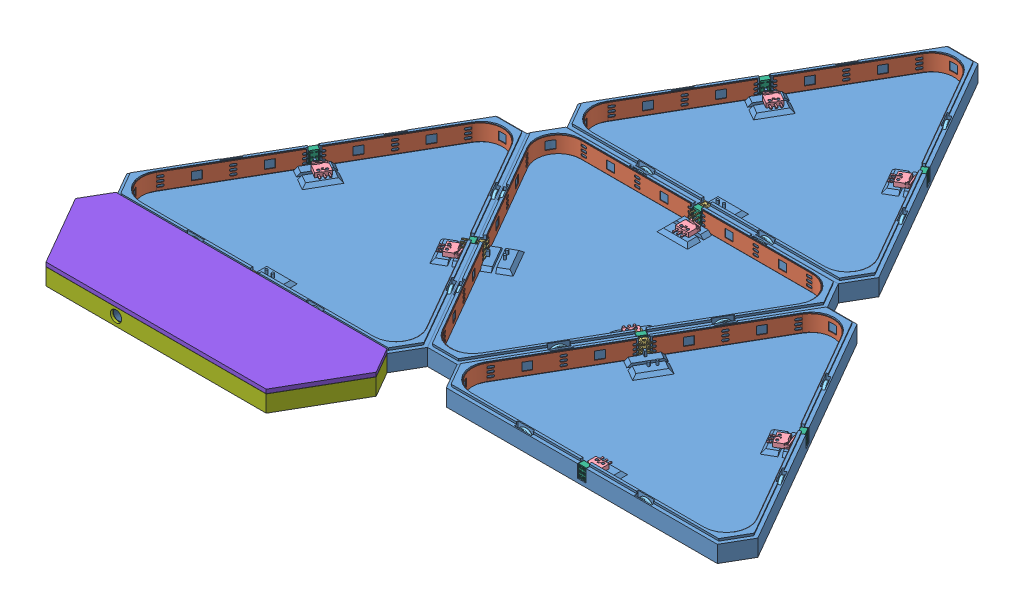
SolidWorks assembly smartleaf_triangle_multi, configuration Défaut. Lengths in mm.
Overall size (448.34 14.05 459.74).
75 component instances, 12 part files, 12 mates.
Components (placement in the parent):
- smartleaf_triangle-1: smartleaf_triangle [Défaut] at (-32.3609 -8.2691 146.7938) size (187.52 14.05 190.18)
  - smartleaf_triangle_bottom-1: smartleaf_triangle_bottom [Défaut] at origin size (187.52 12 162.4)
  - smartleaf_triangle_top-1: smartleaf_triangle_top [Défaut] at (0 13 0) x (1 0 0) z (0 0 -1) size (136.52 2.5 118.23) (hidden)
  - Strip_led_ws2812_30leds-m-1: Strip_led_ws2812_30leds-m [Défaut] at (-125.2022 6.5 104.9223) x (0.5 0 -0.866025) z (0.866025 0 0.5) size (82.78 10 80.82)
  - Strip_led_ws2812_30leds-m-2: Strip_led_ws2812_30leds-m [Défaut] at (153.4665 6.5 55.9671) x (-1 0 0) z (0 0 -1) size (82.78 10 80.82)
  - Strip_led_ws2812_30leds-m-3: Strip_led_ws2812_30leds-m [Défaut] at (-28.2643 6.5 -160.8894) x (0.5 0 0.866025) z (-0.866025 0 0.5) size (82.78 10 80.82)
  - TSM_103_02_T_DV-1: TSM_103_02_T_DV [Défaut] at (0 6.5 57.4721) x (0 -1 0) z (-1 0 0) size (7.62 11.94 7.44)
  - TS0101F020P-1: TS0101F020P [Défaut] at (42.2907 4.35 -22.6845) x (-0.5 0 -0.866025) z (0.866025 0 -0.5) size (8.31 2.7 12.18)
  - TS0101F020P-5: TS0101F020P [Défaut] at (-40.7907 4.35 -25.2826) x (-0.5 0 0.866025) z (-0.866025 0 -0.5) size (8.31 2.7 12.18)
  - Aimant_10x2mm-1: Aimant_10x2mm [Défaut] at (37.5 6 56.4671) x (0.78482 -0.619723 0) z (0 0 1) size (10 10 2)
  - Aimant_10x2mm-2: Aimant_10x2mm [Défaut] at (-37.5 6 56.6671) x (0.873152 -0.487449 0) z (0 0 1) size (10 10 2)
  - Aimant_10x2mm-4: Aimant_10x2mm [Défaut] at (-67.8251 6 4.1424) x (-0.272453 -0.838497 0.471903) z (-0.866025 0 -0.5) size (10 10 2)
  - Aimant_10x2mm-6: Aimant_10x2mm [Défaut] at (-30.3251 6 -60.8095) x (-0.128011 -0.966671 0.221722) z (-0.866025 0 -0.5) size (10 10 2)
  - Aimant_10x2mm-8: Aimant_10x2mm [Défaut] at (30.3251 6 -60.8095) x (-0.4998 -0.028255 -0.86568) z (0.866025 0 -0.5) size (10 10 2)
  - Aimant_10x2mm-10: Aimant_10x2mm [Défaut] at (67.8251 6 4.1424) x (-0.49797 -0.09001 -0.86251) z (0.866025 0 -0.5) size (10 10 2)
  - 610006243021-1: 610006243021 [Défaut] at (-49.638 6.5 -28.6585) x (0 1 0) z (-0.866025 0 -0.5) size (7.62 7.21 3.7)
  - 610006243021-2: 610006243021 [Défaut] at (49.638 6.5 -28.6585) x (0 1 0) z (0.866025 0 -0.5) size (7.62 7.21 3.7)
- smartleaf_triangle-2: smartleaf_triangle [Défaut] at (70.6391 -8.2691 87.3267) x (0.5 0 0.866025) z (-0.866025 0 0.5) size (187.52 14.05 190.18)
  - smartleaf_triangle_bottom-1: smartleaf_triangle_bottom [Défaut] at origin size (187.52 12 162.4)
  - smartleaf_triangle_top-1: smartleaf_triangle_top [Défaut] at (0 13 0) x (1 0 0) z (0 0 -1) size (136.52 2.5 118.23) (hidden)
  - Strip_led_ws2812_30leds-m-1: Strip_led_ws2812_30leds-m [Défaut] at (-125.2022 6.5 104.9223) x (0.5 0 -0.866025) z (0.866025 0 0.5) size (82.78 10 80.82)
  - Strip_led_ws2812_30leds-m-2: Strip_led_ws2812_30leds-m [Défaut] at (153.4665 6.5 55.9671) x (-1 0 0) z (0 0 -1) size (82.78 10 80.82)
  - Strip_led_ws2812_30leds-m-3: Strip_led_ws2812_30leds-m [Défaut] at (-28.2643 6.5 -160.8894) x (0.5 0 0.866025) z (-0.866025 0 0.5) size (82.78 10 80.82)
  - TSM_103_02_T_DV-1: TSM_103_02_T_DV [Défaut] at (0 6.5 57.4721) x (0 -1 0) z (-1 0 0) size (7.62 11.94 7.44)
  - TS0101F020P-1: TS0101F020P [Défaut] at (42.2907 4.35 -22.6845) x (-0.5 0 -0.866025) z (0.866025 0 -0.5) size (8.31 2.7 12.18)
  - TS0101F020P-5: TS0101F020P [Défaut] at (-40.7907 4.35 -25.2826) x (-0.5 0 0.866025) z (-0.866025 0 -0.5) size (8.31 2.7 12.18)
  - Aimant_10x2mm-1: Aimant_10x2mm [Défaut] at (37.5 6 56.4671) x (0.78482 -0.619723 0) z (0 0 1) size (10 10 2)
  - Aimant_10x2mm-2: Aimant_10x2mm [Défaut] at (-37.5 6 56.6671) x (0.873152 -0.487449 0) z (0 0 1) size (10 10 2)
  - Aimant_10x2mm-4: Aimant_10x2mm [Défaut] at (-67.8251 6 4.1424) x (-0.272453 -0.838497 0.471903) z (-0.866025 0 -0.5) size (10 10 2)
  - Aimant_10x2mm-6: Aimant_10x2mm [Défaut] at (-30.3251 6 -60.8095) x (-0.128011 -0.966671 0.221722) z (-0.866025 0 -0.5) size (10 10 2)
  - Aimant_10x2mm-8: Aimant_10x2mm [Défaut] at (30.3251 6 -60.8095) x (-0.4998 -0.028255 -0.86568) z (0.866025 0 -0.5) size (10 10 2)
  - Aimant_10x2mm-10: Aimant_10x2mm [Défaut] at (67.8251 6 4.1424) x (-0.49797 -0.09001 -0.86251) z (0.866025 0 -0.5) size (10 10 2)
  - 610006243021-1: 610006243021 [Défaut] at (-49.638 6.5 -28.6585) x (0 1 0) z (-0.866025 0 -0.5) size (7.62 7.21 3.7)
  - 610006243021-2: 610006243021 [Défaut] at (49.638 6.5 -28.6585) x (0 1 0) z (0.866025 0 -0.5) size (7.62 7.21 3.7)
- smartleaf_triangle-3: smartleaf_triangle [Défaut] at (173.6391 -8.2691 146.7938) x (-0.5 0 0.866025) z (-0.866025 0 -0.5) size (187.52 14.05 190.18)
  - smartleaf_triangle_bottom-1: smartleaf_triangle_bottom [Défaut] at origin size (187.52 12 162.4)
  - smartleaf_triangle_top-1: smartleaf_triangle_top [Défaut] at (0 13 0) x (1 0 0) z (0 0 -1) size (136.52 2.5 118.23) (hidden)
  - Strip_led_ws2812_30leds-m-1: Strip_led_ws2812_30leds-m [Défaut] at (-125.2022 6.5 104.9223) x (0.5 0 -0.866025) z (0.866025 0 0.5) size (82.78 10 80.82)
  - Strip_led_ws2812_30leds-m-2: Strip_led_ws2812_30leds-m [Défaut] at (153.4665 6.5 55.9671) x (-1 0 0) z (0 0 -1) size (82.78 10 80.82)
  - Strip_led_ws2812_30leds-m-3: Strip_led_ws2812_30leds-m [Défaut] at (-28.2643 6.5 -160.8894) x (0.5 0 0.866025) z (-0.866025 0 0.5) size (82.78 10 80.82)
  - TSM_103_02_T_DV-1: TSM_103_02_T_DV [Défaut] at (0 6.5 57.4721) x (0 -1 0) z (-1 0 0) size (7.62 11.94 7.44)
  - TS0101F020P-1: TS0101F020P [Défaut] at (42.2907 4.35 -22.6845) x (-0.5 0 -0.866025) z (0.866025 0 -0.5) size (8.31 2.7 12.18)
  - TS0101F020P-5: TS0101F020P [Défaut] at (-40.7907 4.35 -25.2826) x (-0.5 0 0.866025) z (-0.866025 0 -0.5) size (8.31 2.7 12.18)
  - Aimant_10x2mm-1: Aimant_10x2mm [Défaut] at (37.5 6 56.4671) x (0.78482 -0.619723 0) z (0 0 1) size (10 10 2)
  - Aimant_10x2mm-2: Aimant_10x2mm [Défaut] at (-37.5 6 56.6671) x (0.873152 -0.487449 0) z (0 0 1) size (10 10 2)
  - Aimant_10x2mm-4: Aimant_10x2mm [Défaut] at (-67.8251 6 4.1424) x (-0.272453 -0.838497 0.471903) z (-0.866025 0 -0.5) size (10 10 2)
  - Aimant_10x2mm-6: Aimant_10x2mm [Défaut] at (-30.3251 6 -60.8095) x (-0.128011 -0.966671 0.221722) z (-0.866025 0 -0.5) size (10 10 2)
  - Aimant_10x2mm-8: Aimant_10x2mm [Défaut] at (30.3251 6 -60.8095) x (-0.4998 -0.028255 -0.86568) z (0.866025 0 -0.5) size (10 10 2)
  - Aimant_10x2mm-10: Aimant_10x2mm [Défaut] at (67.8251 6 4.1424) x (-0.49797 -0.09001 -0.86251) z (0.866025 0 -0.5) size (10 10 2)
  - 610006243021-1: 610006243021 [Défaut] at (-49.638 6.5 -28.6585) x (0 1 0) z (-0.866025 0 -0.5) size (7.62 7.21 3.7)
  - 610006243021-2: 610006243021 [Défaut] at (49.638 6.5 -28.6585) x (0 1 0) z (0.866025 0 -0.5) size (7.62 7.21 3.7)
- smartleaf_triangle-4: smartleaf_triangle [Défaut] at (70.6391 -8.2691 -31.6075) size (187.52 14.05 190.18)
  - smartleaf_triangle_bottom-1: smartleaf_triangle_bottom [Défaut] at origin size (187.52 12 162.4)
  - smartleaf_triangle_top-1: smartleaf_triangle_top [Défaut] at (0 13 0) x (1 0 0) z (0 0 -1) size (136.52 2.5 118.23) (hidden)
  - Strip_led_ws2812_30leds-m-1: Strip_led_ws2812_30leds-m [Défaut] at (-125.2022 6.5 104.9223) x (0.5 0 -0.866025) z (0.866025 0 0.5) size (82.78 10 80.82)
  - Strip_led_ws2812_30leds-m-2: Strip_led_ws2812_30leds-m [Défaut] at (153.4665 6.5 55.9671) x (-1 0 0) z (0 0 -1) size (82.78 10 80.82)
  - Strip_led_ws2812_30leds-m-3: Strip_led_ws2812_30leds-m [Défaut] at (-28.2643 6.5 -160.8894) x (0.5 0 0.866025) z (-0.866025 0 0.5) size (82.78 10 80.82)
  - TSM_103_02_T_DV-1: TSM_103_02_T_DV [Défaut] at (0 6.5 57.4721) x (0 -1 0) z (-1 0 0) size (7.62 11.94 7.44)
  - TS0101F020P-1: TS0101F020P [Défaut] at (42.2907 4.35 -22.6845) x (-0.5 0 -0.866025) z (0.866025 0 -0.5) size (8.31 2.7 12.18)
  - TS0101F020P-5: TS0101F020P [Défaut] at (-40.7907 4.35 -25.2826) x (-0.5 0 0.866025) z (-0.866025 0 -0.5) size (8.31 2.7 12.18)
  - Aimant_10x2mm-1: Aimant_10x2mm [Défaut] at (37.5 6 56.4671) x (0.78482 -0.619723 0) z (0 0 1) size (10 10 2)
  - Aimant_10x2mm-2: Aimant_10x2mm [Défaut] at (-37.5 6 56.6671) x (0.873152 -0.487449 0) z (0 0 1) size (10 10 2)
  - Aimant_10x2mm-4: Aimant_10x2mm [Défaut] at (-67.8251 6 4.1424) x (-0.272453 -0.838497 0.471903) z (-0.866025 0 -0.5) size (10 10 2)
  - Aimant_10x2mm-6: Aimant_10x2mm [Défaut] at (-30.3251 6 -60.8095) x (-0.128011 -0.966671 0.221722) z (-0.866025 0 -0.5) size (10 10 2)
  - Aimant_10x2mm-8: Aimant_10x2mm [Défaut] at (30.3251 6 -60.8095) x (-0.4998 -0.028255 -0.86568) z (0.866025 0 -0.5) size (10 10 2)
  - Aimant_10x2mm-10: Aimant_10x2mm [Défaut] at (67.8251 6 4.1424) x (-0.49797 -0.09001 -0.86251) z (0.866025 0 -0.5) size (10 10 2)
  - 610006243021-1: 610006243021 [Défaut] at (-49.638 6.5 -28.6585) x (0 1 0) z (-0.866025 0 -0.5) size (7.62 7.21 3.7)
  - 610006243021-2: 610006243021 [Défaut] at (49.638 6.5 -28.6585) x (0 1 0) z (0.866025 0 -0.5) size (7.62 7.21 3.7)
- smartleaf_controller-1: smartleaf_controller [Défaut] at (-32.3609 -8.2691 265.7279) size (204.69 13 192.13)
  - smartleaf_controller_bottom-1: smartleaf_controller_bottom [Défaut] x (0.5 0 -0.866025) z (0.866025 0 0.5) size (128.1 12 162.4)
  - smartleaf_controller_top-1: smartleaf_controller_top [Défaut] at (0 13 0) x (1 0 0) z (0 -1 0) size (187.52 59.47 4.8)
  - ESP32_Mini_full-1: ESP32_Mini_full [Défaut] at (28 5.1 -36.8171) x (0 0 1) z (-1 0 0) size (31.2 3.67 39)
  - 610006243021-1: 610006243021 [Défaut] at (0 6.5 -42.7626) x (0 1 0) z (0 0 -1) size (7.62 7.21 3.7)
  - 61300625721-1: 61300625721 [Défaut] at (0 6.5 -43.5034) x (0 -1 0) z (0 0 -1) size (8.22 5.33 8.1) (hidden)
  - 694106301002-1: 694106301002 [Default] at (-23.85 5.5 -5) x (0 1 0) z (-1 0 0) size (9.5 14.5 14.5)
Mates (geometry in assembly coordinates):
- Coïncidente1: coincident: plane of smartleaf_triangle-1/smartleaf_triangle_bottom-1 through (-32.3609 -8.2691 146.7938) normal (0 -1 0); plane of smartleaf_triangle-2/smartleaf_triangle_bottom-1 through (70.6391 -8.2691 87.3267) normal (0 -1 0)
- Coïncidente2: coincident: plane of smartleaf_triangle-1/smartleaf_triangle_bottom-1 through (70.6391 3.7309 206.2608) normal (0.866025 0 -0.5); plane of smartleaf_triangle-2/smartleaf_triangle_bottom-1 through (-32.3609 3.7309 27.8596) normal (-0.866025 0 0.5)
- Coïncidente3: coincident: plane of smartleaf_triangle-1/smartleaf_triangle_bottom-1 through (-32.3609 -8.2691 146.7938) normal (0.5 0 0.866025); plane of smartleaf_triangle-2/smartleaf_triangle_bottom-1 through (70.6391 -8.2691 87.3267) normal (-0.5 0 -0.866025)
- Coïncidente4: coincident: plane of smartleaf_triangle-1/smartleaf_triangle_bottom-1 through (-32.3609 -8.2691 146.7938) normal (0 -1 0); plane of smartleaf_triangle-3/smartleaf_triangle_bottom-1 through (173.6391 -8.2691 146.7938) normal (0 -1 0)
- Coïncidente5: coincident: plane of smartleaf_triangle-2/smartleaf_triangle_bottom-1 through (70.6391 3.7309 206.2608) normal (0.866025 0 0.5); plane of smartleaf_triangle-3/smartleaf_triangle_bottom-1 through (173.6391 3.7309 27.8596) normal (-0.866025 0 -0.5)
- Coïncidente6: coincident: plane of smartleaf_triangle-2/smartleaf_triangle_bottom-1 through (70.6391 -8.2691 87.3267) normal (-0.5 0 0.866025); plane of smartleaf_triangle-3/smartleaf_triangle_bottom-1 through (173.6391 -8.2691 146.7938) normal (0.5 0 -0.866025)
- Coïncidente7: coincident: plane of smartleaf_triangle-1/smartleaf_triangle_bottom-1 through (-32.3609 -8.2691 146.7938) normal (0 -1 0); plane of smartleaf_triangle-4/smartleaf_triangle_bottom-1 through (70.6391 -8.2691 -31.6075) normal (0 -1 0)
- Coïncidente9: coincident: plane of smartleaf_triangle-2/smartleaf_triangle_bottom-1 through (70.6391 -8.2691 87.3267) normal (-1 0 0); plane of smartleaf_triangle-4/smartleaf_triangle_bottom-1 through (70.6391 -8.2691 -31.6075) normal (-1 0 0)
- Coïncidente11: coincident: plane of smartleaf_triangle-2/smartleaf_triangle_bottom-1 through (173.6391 3.7309 27.8596) normal (0 0 -1); plane of smartleaf_triangle-4/smartleaf_triangle_bottom-1 through (-32.3609 3.7309 27.8596) normal (0 0 1)
- Coïncidente12: coincident: plane of smartleaf_triangle-1/smartleaf_triangle_bottom-1 through (-135.3609 3.7309 206.2608) normal (0 0 1); plane of smartleaf_controller-1/smartleaf_controller_bottom-1 through (70.6391 3.7309 206.2608) normal (0 0 -1)
- Coïncidente13: coincident: plane of smartleaf_triangle-1/smartleaf_triangle_bottom-1 through (-32.3609 -8.2691 146.7938) normal (0 -1 0); plane of smartleaf_controller-1/smartleaf_controller_bottom-1 through (-32.3609 -8.2691 265.7279) normal (0 -1 0)
- Coïncidente14: coincident: plane of smartleaf_triangle-1/smartleaf_triangle_bottom-1 through (-32.3609 -8.2691 146.7938) normal (1 0 0); plane of smartleaf_controller-1 through (-32.3609 -8.2691 265.7279) normal (1 0 0)
